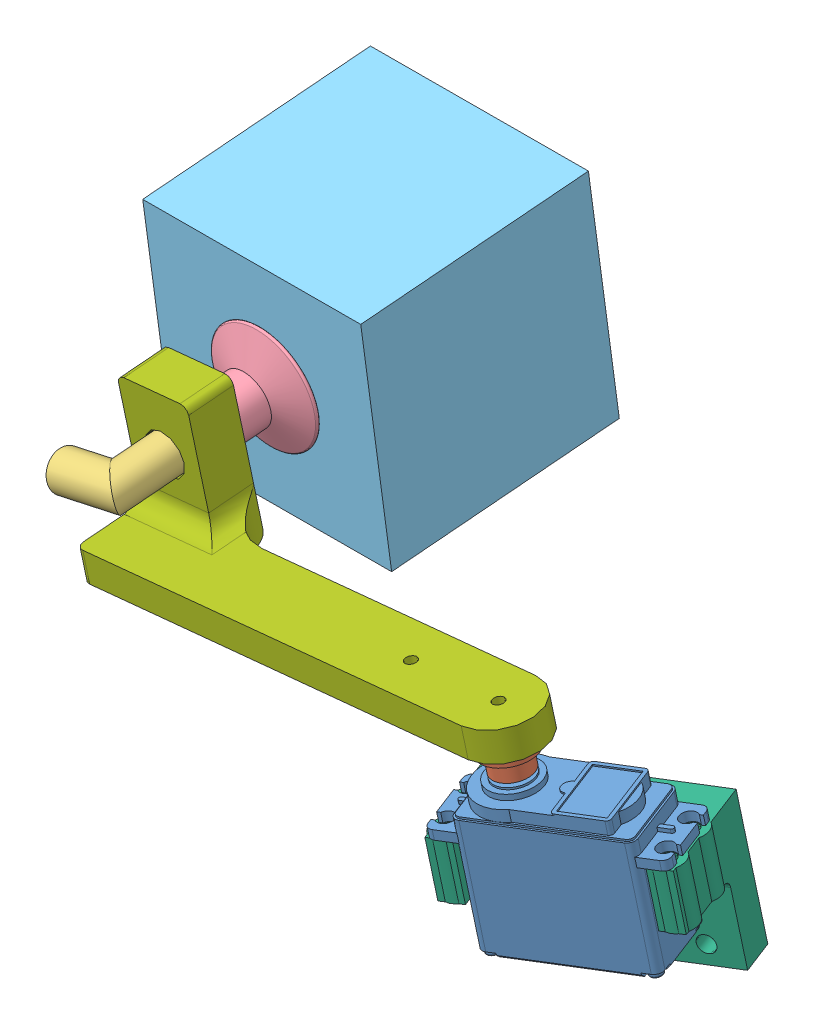
SolidWorks assembly 129, configuration Default. Lengths in mm.
Overall size (178.97 110.73 115.34).
7 component instances, 7 part files, 16 mates.
Components (placement in the parent):
- Servo-D-2: Servo-D [По умолчанию] at (-27.7698 -9.9027 55.395) x (0.934112 0.15972 -0.319256) z (0.331168 -0.053828 0.942035) size (53 41.52 20)
- 2__v-2: 2__v [Default] at (-42.3087 26.9421 62.6114) x (0.990824 0.130156 0.036441) z (-0.133277 0.985694 0.103176) size (41 14 8)
- 128-1: 128 [Default] at (-160.1402 40.1971 66.4035) x (-0.967007 -0.25003 -0.048816) z (0.022491 0.107086 -0.993995) size (20 10 20)
- phan-1: phan [Défaut] at (-144.8255 47.8026 31.3519) x (0.036163 0.993509 0.107852) z (-0.999093 0.038372 -0.018472) size (29.46 25.39 29.46)
- statuettee-1: statuettee [Default] at (-144.7266 48.2731 26.9851) x (0.031492 -0.993829 -0.106355) z (0.022491 0.107086 -0.993995) size (61 61 61)
- 158-1: 158 [Default] at (-35.8279 4.1804 38.8634) x (0.934112 0.15972 -0.319256) z (0.331168 -0.053828 0.942035) size (56.04 36.5 28.27)
- 127_3-1: 127_3 [Default] at (-128.6612 31.6499 61.1647) x (0.990824 0.130156 0.036441) z (0.133277 -0.985694 -0.103176) size (120 30.6 38)
Mates (geometry in assembly coordinates):
- Concentric3: concentric aligned: cylinder of Servo-D-2 through (-42.6419 29.4063 62.8693) axis (0.133277 -0.985694 -0.103176) radius 3; cylinder of 2__v-2 through (-42.9751 31.8706 63.1273) axis (0.133277 -0.985694 -0.103176) radius 3
- Distance3: distance = 1 mm anti-aligned: plane of 2__v-2 through (-42.3087 26.9421 62.6114) normal (0.133277 -0.985694 -0.103176); plane of Servo-D-2 through (-42.1754 25.9564 62.5082) normal (-0.133277 0.985694 0.103176)
- Concentric5: concentric aligned: cylinder of 128-1 through (-145.7611 43.3479 72.7021) axis (0.022491 0.107086 -0.993995) radius 5; cylinder of phan-1 through (-145.2978 45.5538 52.2258) axis (0.022491 0.107086 -0.993995) radius 6.75
- Coincident13: coincident aligned: circle of phan-1; plane of statuettee-1 through (-144.7266 48.2731 26.9851) normal (-0.022491 -0.107086 0.993995)
- Width5: width: plane of statuettee-1 through (-113.8381 85.9989 -29.6202) normal (-0.031492 0.993829 0.106355); plane of phan-1 through (-111.9171 25.3753 -36.1078) normal (0.031492 -0.993829 -0.106355); cylinder of statuettee-1 through (-145.2978 45.5538 52.2258) axis (0.022491 0.107086 -0.993995) radius 6.75
- Width6: width: plane of statuettee-1 through (-172.8714 23.6117 -37.677) normal (-0.999251 -0.028911 -0.025724); plane of phan-1 through (-111.9171 25.3753 -36.1078) normal (0.999251 0.028911 0.025724); cylinder of statuettee-1 through (-145.2978 45.5538 52.2258) axis (0.022491 0.107086 -0.993995) radius 6.75
- Parallel1: parallel anti-aligned: plane of Servo-D-2 through (-52.227 19.7956 55.0744) normal (-0.331168 0.053828 -0.942035); plane of 158-1 through (-32.8474 3.696 47.3417) normal (0.331168 -0.053828 0.942035)
- Width8: width aligned: plane of 158-1 through (-59.8343 12.444 57.3287) normal (-0.934112 -0.15972 0.319256); plane of Servo-D-2 through (-9.3923 21.0689 40.0889) normal (0.934112 0.15972 -0.319256); plane of 158-1 through (-48.1342 18.5073 72.6696) normal (-0.934112 -0.15972 0.319256); plane of Servo-D-2 through (-10.7697 24.8961 59.8993) normal (0.934112 0.15972 -0.319256)
- Coincident17: coincident anti-aligned: plane of Servo-D-2 through (-56.9095 12.6888 58.7683) normal (0.133277 -0.985694 -0.103176); plane of 158-1 through (-59.8343 12.444 57.3287) normal (-0.133277 0.985694 0.103176)
- Concentric6: concentric anti-aligned: cylinder of 2__v-2 through (-43.3749 34.8277 63.4368) axis (0.133277 -0.985694 -0.103176) radius 7; cylinder of 127_3-1 through (-43.3749 34.8277 63.4368) axis (-0.133277 0.985694 0.103176) radius 10
- Width9: width anti-aligned: plane of 127_3-1 through (-152.5904 19.4396 69.3682) normal (-0.022491 -0.107086 0.993995); plane of 2__v-2 through (-152.1406 21.5813 49.4883) normal (0.022491 0.107086 -0.993995); plane of 127_3-1 through (-73.1896 30.4946 66.3196) normal (-0.12097 -0.119505 0.985436); plane of 2__v-2 through (-73.0097 31.3513 58.3676) normal (-0.076212 0.093603 -0.992688)
- Coincident18: coincident anti-aligned: plane of Servo-D-2 through (-52.227 19.7956 55.0744) normal (-0.331168 0.053828 -0.942035); plane of 158-1 through (-32.8474 3.696 47.3417) normal (0.331168 -0.053828 0.942035)
- Coincident19: coincident anti-aligned: plane of 2__v-2 through (-73.0996 30.923 62.3436) normal (-0.133277 0.985694 0.103176); plane of 127_3-1 through (-43.3749 34.8277 63.4368) normal (0.133277 -0.985694 -0.103176)
- Concentric7: concentric aligned: cylinder of phan-1 through (-145.2978 45.5538 52.2258) axis (0.022491 0.107086 -0.993995) radius 6.75; cylinder of 127_3-1 through (-145.5227 44.483 62.1657) axis (0.022491 0.107086 -0.993995) radius 5.5
- Coincident20: coincident anti-aligned: plane of phan-1 through (-145.2978 45.5538 52.2258) normal (-0.022491 -0.107086 0.993995); plane of 127_3-1 through (-128.4362 32.7208 51.2248) normal (0.022491 0.107086 -0.993995)
- Coincident21: coincident anti-aligned: plane of 128-1 through (-145.2978 45.5538 52.2258) normal (0.022491 0.107086 -0.993995); plane of phan-1 through (-145.2978 45.5538 52.2258) normal (-0.022491 -0.107086 0.993995)
